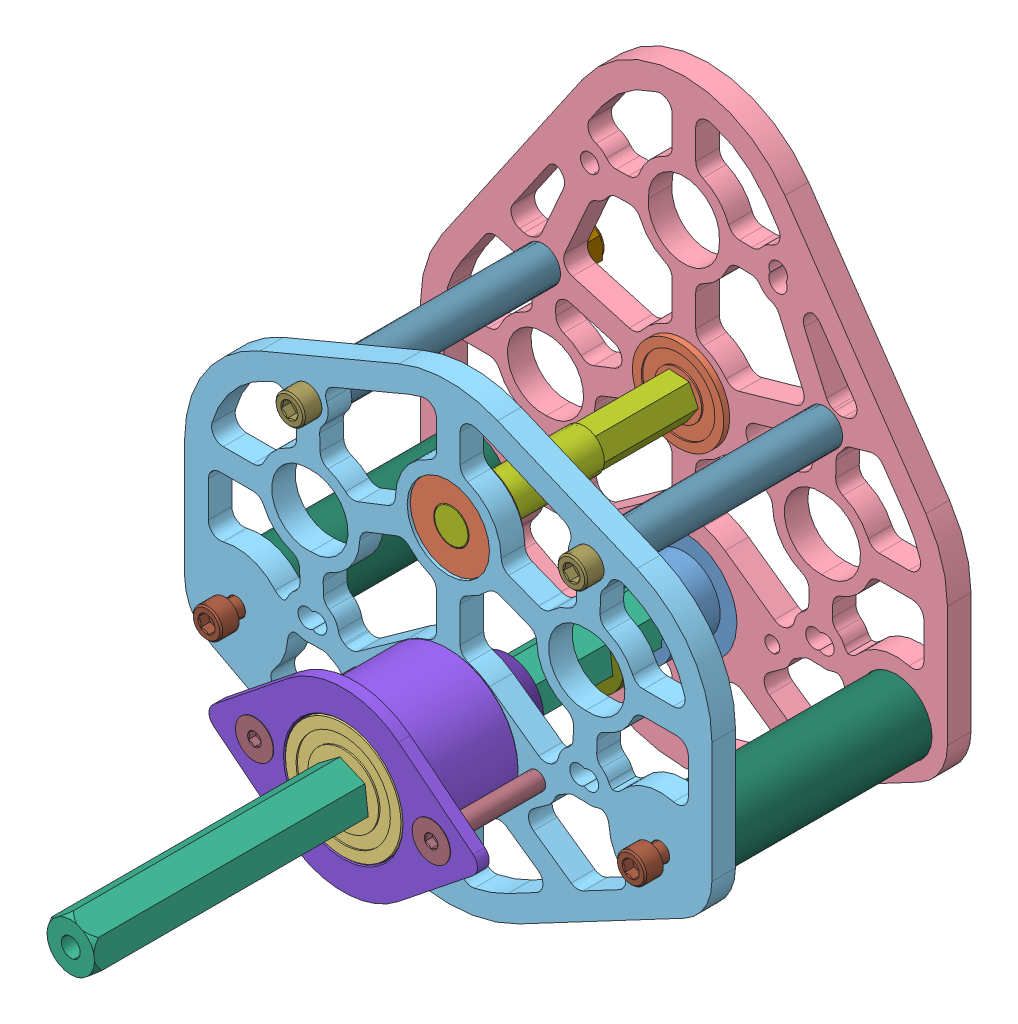
SolidWorks assembly WCP SS Gearbox, configuration Default. Lengths in mm.
Overall size (142.06 161.39 181.1).
30 component instances, 20 part files, 62 mates.
Components (placement in the parent):
- 217-2731-1: 217-2731 [Default] at (0 -47.0408 6.35) x (0.182541 -0.983198 0) z (0.983198 0.182541 0) size (31.12 7.94 31.12)
- 217-2733-1: 217-2733 [Default] at (0 0 7.9375) x (0 0 -1) z (0.981737 -0.190242 0) size (7.11 24.61 24.61)
- 217-2733-2: 217-2733 [Default] at (0 0 61.9125) x (0 0 1) z (-0.773016 -0.634387 0) size (7.11 24.61 24.61)
- 217-2734-1: 217-2734 [Default] at (0 -47.0408 90.2335) x (0.800075 0.5999 0) z (0.5999 -0.800075 0) size (31.12 7.94 31.12)
- 217-3421-001 Rev1-1: 217-3421-001 Rev1 [Default] at origin size (142.02 161.39 6.35)
- 217-3421-002 Rev1-1: 217-3421-002 Rev1 [Default] at (0 0 69.85) x (-1 0 0) z (0 0 -1) size (142.06 121.97 6.35)
- 217-3421-004 Rev1-1: 217-3421-004 Rev1 [Default] at (-0.0106 -47.0363 89.027) x (-0.919566 0.392935 0) z (0 0 1) size (15.59 12.7 175.64)
- 217-3422-001 Rev1-1: 217-3422-001 Rev1 [Default] at (0 0 34.925) x (0.99796 -0.063837 0) z (0 0 1) size (11.11 11.11 68.26)
- 217-3422-004 Rev2-1: 217-3422-004 Rev2 [Default] at (0 -47.0408 96.5835) size (72.39 47.62 34.67)
- 217-3421-010 Rev1-1: 217-3421-010 Rev1 [Default] at (57.15 -47.0408 0) x (0.608161 -0.793814 0) z (0.793814 0.608161 0) size (9.53 6.13 11)
- 217-3421-010 Rev1-2: 217-3421-010 Rev1 [Default] at (-57.15 -47.0408 0) x (0.608161 -0.793814 0) z (0.793814 0.608161 0) size (9.53 6.13 11)
- 217-3421-011 Rev2_97633A200-1: 217-3421-011 Rev2_97633A200 [Default] at (-0.0106 -47.0363 -2.032) x (0 0 -1) z (0.969555 0.244872 0) size (0.89 16.1 14.34)
- 217-3422-005 Rev1-1: 217-3422-005 Rev1 [Default] at (57.15 -47.0408 73.025) x (0 0 -1) z (-0.705988 0.708224 0) size (87.6 7.92 7.92)
- 217-3422-005 Rev1-2: 217-3422-005 Rev1 [Default] at (-57.15 -47.0408 73.025) x (0 0 -1) z (-0.705988 0.708224 0) size (87.6 7.92 7.92)
- 217-3422-006 Rev1-1: 217-3422-006 Rev1 [Default] at (38.0118 10.8086 69.85) x (0 0 -1) z (-0.961271 0.275605 0) size (81.25 7.92 7.92)
- 217-3422-006 Rev1-2: 217-3422-006 Rev1 [Default] at (-38.0118 10.8086 69.85) x (0 0 -1) z (-0.961271 0.275605 0) size (81.25 7.92 7.92)
- 217-3422-007 Rev1-1: 217-3422-007 Rev1 [Default] at (23.8125 -47.0408 95.0723) x (0 0 1) z (-0.888615 -0.458653 0) size (35.11 10.21 10.21)
- 217-3422-007 Rev1-2: 217-3422-007 Rev1 [Default] at (-23.8125 -47.0408 95.0723) x (0 0 1) z (-0.86839 -0.495881 0) size (35.11 10.21 10.21)
- 217-3422-002 Rev1-1: 217-3422-002 Rev1 [Default] at (-38.0118 10.8086 34.925) size (9.53 9.53 57.15)
- 217-3422-002 Rev1-2: 217-3422-002 Rev1 [Default] at (38.0118 10.8086 34.925) size (9.53 9.53 57.15)
- 217-3422-003 Rev1-1: 217-3422-003 Rev1 [Default] at (-57.15 -47.0408 34.925) x (0.999998 0.002183 0) z (0 0 1) size (19.13 19.13 63.5)
- 217-3422-003 Rev1-2: 217-3422-003 Rev1 [Default] at (57.15 -47.0408 34.925) x (0.852021 0.523507 0) z (0 0 1) size (19.13 19.13 63.5)
- 217-3257-001 Rev1-1: 217-3257-001 Rev1 [Default] at (0 -47.0408 31.5785) x (0.800075 0.5999 0) z (0 0 1) size (19.5 19.5 1.59)
- 217-2758-001 Rev1-1: 217-2758-001 Rev1 [Default] at (0 -47.0408 55.3085) x (-0.5999 0.800075 0) z (0 0 1) size (19.05 19.05 3.17)
- 217-3259-001 Rev1-1: 217-3259-001 Rev1 [Default] at (0 -47.0408 60.071) x (-0.919566 0.392935 0) z (0 0 1) size (19.5 19.5 6.35)
- 217-3261-001 Rev1-1: 217-3261-001 Rev1 [Default] at (0 -47.0408 12.7) size (19.5 19.5 12.7)
- 217-3263-001 Rev1-1: 217-3263-001 Rev1 [Default] at (0 -47.0408 77.5335) x (0.919566 -0.392935 0) z (0 0 1) size (19.5 19.5 25.4)
- 217-3257-001 Rev1-2: 217-3257-001 Rev1 [Default] at (0 -47.0408 64.0398) x (0.800075 0.5999 0) z (0 0 1) size (19.5 19.5 1.59)
- 217-3421-010 Rev1-3: 217-3421-010 Rev1 [Default] at (38.0118 10.8086 0) x (0.608161 -0.793814 0) z (0.793814 0.608161 0) size (9.53 6.13 11)
- 217-3421-010 Rev1-4: 217-3421-010 Rev1 [Default] at (-38.0118 10.8086 0) x (0.608161 -0.793814 0) z (0.793814 0.608161 0) size (9.53 6.13 11)
Mates (geometry in assembly coordinates):
- Coincident2: coincident anti-aligned: plane of 217-2734-1 through (-0.8775 -39.7495 90.2335) normal (0.5999 -0.800075 0); plane of 217-3421-004 Rev1-1 through (-0.8868 -39.7564 171.577) normal (-0.5999 0.800075 0)
- Coincident3: coincident anti-aligned: plane of 217-2734-1 through (-6.7532 -44.1551 90.2335) normal (0.992835 0.119491 0); plane of 217-3421-004 Rev1-1 through (-6.7532 -44.1551 171.577) normal (-0.992835 -0.119491 0)
- Concentric1: concentric anti-aligned: cylinder of 217-2734-1 through (0 -47.0408 90.2335) axis (0 0 1) radius 14.2748; cylinder of 217-3422-004 Rev2-1 through (0 -47.0408 98.171) axis (0 0 -1) radius 14.2748
- Coincident4: coincident anti-aligned: plane of 217-2734-1 through (12.4472 -37.7079 96.5835) normal (0 0 -1); plane of 217-3422-004 Rev2-1 through (0 -47.0408 96.5835) normal (0 0 1)
- Concentric2: concentric aligned: cylinder of 217-3422-004 Rev2-1 through (23.8125 -47.0408 98.171) axis (0 0 1) radius 2.5527; cylinder of 217-3422-007 Rev1-1 through (23.8125 -47.0408 63.3731) axis (0 0 1) radius 2.413
- Coincident6: coincident anti-aligned: plane of 217-3422-004 Rev2-1 through (0 -47.0408 98.171) normal (0 0 1); circle of 217-3422-007 Rev1-1
- Concentric5: concentric aligned: cylinder of 217-3422-004 Rev2-1 through (-23.8125 -47.0408 98.171) axis (0 0 1) radius 2.5527; cylinder of 217-3422-007 Rev1-2 through (-23.8125 -47.0408 63.3731) axis (0 0 1) radius 2.413
- Coincident7: coincident anti-aligned: plane of 217-3422-004 Rev2-1 through (0 -47.0408 98.171) normal (0 0 1); circle of 217-3422-007 Rev1-2
- Coincident10: coincident anti-aligned: plane of 217-2734-1 through (11.4209 -38.4773 90.2335) normal (0 0 -1); plane of 217-3263-001 Rev1-1 through (0 -47.0408 90.2335) normal (0 0 1)
- Coincident13: coincident anti-aligned: plane of 217-3263-001 Rev1-1 through (0 -47.0408 64.8335) normal (0 0 -1); plane of 217-3257-001 Rev1-2 through (0 -47.0408 64.8335) normal (0 0 1)
- Parallel1: parallel anti-aligned: plane of 217-3421-004 Rev1-1 through (0.8655 -54.3161 171.577) normal (0.5999 -0.800075 0); plane of 217-3263-001 Rev1-1 through (0.8937 -54.4662 90.2335) normal (-0.5999 0.800075 0)
- Concentric6: concentric anti-aligned: cylinder of 217-2734-1 through (0 -47.0408 90.2335) axis (0 0 1) radius 14.2748; cylinder of 217-3263-001 Rev1-1 through (0 -47.0408 90.2335) axis (0 0 -1) radius 9.75
- Parallel2: parallel anti-aligned: plane of 217-3421-004 Rev1-1 through (-0.8868 -39.7564 171.577) normal (-0.5999 0.800075 0); plane of 217-3257-001 Rev1-2 through (-0.8937 -39.6154 64.8335) normal (0.5999 -0.800075 0)
- Concentric7: concentric aligned: cylinder of 217-3263-001 Rev1-1 through (0 -47.0408 90.2335) axis (0 0 -1) radius 9.75; cylinder of 217-3257-001 Rev1-2 through (0 -47.0408 64.8335) axis (0 0 -1) radius 9.75
- Parallel4: parallel anti-aligned: plane of 217-3421-004 Rev1-1 through (-0.8868 -39.7564 171.577) normal (-0.5999 0.800075 0); plane of 217-3259-001 Rev1-1 through (-0.8937 -39.6154 63.246) normal (0.5999 -0.800075 0)
- Concentric9: concentric aligned: cylinder of 217-3259-001 Rev1-1 through (0 -47.0408 63.246) axis (0 0 -1) radius 9.75; cylinder of 217-3257-001 Rev1-2 through (0 -47.0408 64.8335) axis (0 0 -1) radius 9.75
- Coincident18: coincident anti-aligned: plane of 217-3259-001 Rev1-1 through (0 -47.0408 63.246) normal (0 0 1); plane of 217-3257-001 Rev1-2 through (0 -47.0408 63.246) normal (0 0 -1)
- Concentric10: concentric anti-aligned: cylinder of 217-3421-002 Rev1-1 through (0 -47.0408 63.5) axis (0 0 1) radius 14.2748; cylinder of 217-3422-004 Rev2-1 through (0 -47.0408 123.7315) axis (0 0 -1) radius 14.2621
- Concentric12: concentric anti-aligned: cylinder of 217-3421-002 Rev1-1 through (-23.8125 -47.0408 63.5) axis (0 0 -1) radius 2.0193; cylinder of 217-3422-007 Rev1-2 through (-23.8125 -47.0408 63.3731) axis (0 0 1) radius 2.413
- Coincident19: coincident aligned: plane of 217-3421-002 Rev1-1 through (0 0 69.85) normal (0 0 1); circle of 217-3422-004 Rev2-1
- Concentric13: concentric aligned: cylinder of 217-3421-002 Rev1-1 through (-57.15 -47.0408 66.675) axis (0 0 -1) radius 9.5885; cylinder of 217-3422-003 Rev1-1 through (-57.15 -47.0408 66.675) axis (0 0 -1) radius 9.5631
- Coincident20: coincident anti-aligned: plane of 217-3421-002 Rev1-1 through (-57.15 -47.0408 66.675) normal (0 0 -1); plane of 217-3422-003 Rev1-1 through (-57.15 -47.0408 66.675) normal (0 0 1)
- Concentric14: concentric aligned: cylinder of 217-3421-002 Rev1-1 through (57.15 -47.0408 66.675) axis (0 0 -1) radius 9.5885; cylinder of 217-3422-003 Rev1-2 through (57.15 -47.0408 66.675) axis (0 0 -1) radius 9.5631
- Coincident21: coincident anti-aligned: plane of 217-3421-002 Rev1-1 through (57.15 -47.0408 66.675) normal (0 0 -1); plane of 217-3422-003 Rev1-2 through (57.15 -47.0408 66.675) normal (0 0 1)
- Concentric15: concentric aligned: cylinder of 217-3421-002 Rev1-1 through (57.15 -47.0408 63.5) axis (0 0 1) radius 2.4892; cylinder of 217-3422-005 Rev1-1 through (57.15 -47.0408 -9.525) axis (0 0 1) radius 2.413
- Distance1: distance = 3.175 mm anti-aligned: plane of 217-3421-002 Rev1-1 through (0 0 69.85) normal (0 0 1); plane of 217-3422-005 Rev1-1 through (54.3437 -49.8382 73.025) normal (0 0 -1)
- Concentric16: concentric aligned: cylinder of 217-3421-002 Rev1-1 through (-57.15 -47.0408 63.5) axis (0 0 1) radius 2.4892; cylinder of 217-3422-005 Rev1-2 through (-57.15 -47.0408 -9.525) axis (0 0 1) radius 2.413
- Distance2: distance = 3.175 mm anti-aligned: plane of 217-3421-002 Rev1-1 through (0 0 69.85) normal (0 0 1); plane of 217-3422-005 Rev1-2 through (-59.9563 -49.8382 73.025) normal (0 0 -1)
- Concentric17: concentric aligned: cylinder of 217-3257-001 Rev1-1 through (0 -47.0408 32.3723) axis (0 0 -1) radius 9.75; cylinder of 217-3259-001 Rev1-1 through (0 -47.0408 63.246) axis (0 0 -1) radius 9.75
- Parallel5: parallel anti-aligned: plane of 217-3421-004 Rev1-1 through (5.8558 -42.6376 171.577) normal (0.392935 0.919566 0); plane of 217-3257-001 Rev1-1 through (5.9838 -42.5541 32.3723) normal (-0.392935 -0.919566 0)
- Concentric18: concentric aligned: cylinder of 217-2758-001 Rev1-1 through (0 -47.0408 56.896) axis (0 0 -1) radius 9.525; cylinder of 217-3259-001 Rev1-1 through (0 -47.0408 63.246) axis (0 0 -1) radius 9.75
- Parallel6: parallel anti-aligned: plane of 217-3421-004 Rev1-1 through (-0.8868 -39.7564 171.577) normal (-0.5999 0.800075 0); plane of 217-2758-001 Rev1-1 through (-0.8937 -39.6154 56.896) normal (0.5999 -0.800075 0)
- Coincident28: coincident anti-aligned: plane of 217-2758-001 Rev1-1 through (0 -47.0408 56.896) normal (0 0 1); plane of 217-3259-001 Rev1-1 through (0 -47.0408 56.896) normal (0 0 -1)
- Distance3: distance = 21.3487 mm anti-aligned: plane of 217-2758-001 Rev1-1 through (0 -47.0408 53.721) normal (0 0 -1); plane of 217-3257-001 Rev1-1 through (0 -47.0408 32.3723) normal (0 0 1)
- Concentric19: concentric anti-aligned: cylinder of 217-2733-2 through (0 0 61.9125) axis (0 0 -1) radius 11.1125; cylinder of 217-3421-002 Rev1-1 through (0 0 63.5) axis (0 0 1) radius 11.0998
- Coincident31: coincident anti-aligned: plane of 217-2733-2 through (-7.0496 8.5901 63.5) normal (0 0 1); plane of 217-3421-002 Rev1-1 through (0 0 63.5) normal (0 0 -1)
- Concentric20: concentric aligned: cylinder of 217-2733-2 through (0 0 61.9125) axis (0 0 -1) radius 4.7625; cylinder of 217-3422-001 Rev1-1 through (0 0 69.0563) axis (0 0 -1) radius 4.7498
- Coincident32: coincident anti-aligned: plane of 217-2733-2 through (-4.0284 4.9086 61.9125) normal (0 0 -1); plane of 217-3422-001 Rev1-1 through (0 0 61.9125) normal (0 0 1)
- Concentric24: concentric aligned: cylinder of 217-2731-1 through (0 -47.0408 6.35) axis (0 0 -1) radius 14.2875; cylinder of 217-3421-001 Rev1-1 through (0 -47.0408 6.35) axis (0 0 -1) radius 14.2748
- Coincident38: coincident anti-aligned: plane of 217-2731-1 through (2.8399 -62.3369 0) normal (0 0 1); plane of 217-3421-001 Rev1-1 through (0 0 0) normal (0 0 -1)
- Concentric25: concentric aligned: cylinder of 217-2731-1 through (0 -47.0408 6.35) axis (0 0 -1) radius 6.35; cylinder of 217-3261-001 Rev1-1 through (0 -47.0408 19.05) axis (0 0 -1) radius 9.75
- Coincident39: coincident anti-aligned: plane of 217-2731-1 through (2.6081 -61.0882 6.35) normal (0 0 1); plane of 217-3261-001 Rev1-1 through (0 -47.0408 6.35) normal (0 0 -1)
- Concentric27: concentric aligned: cylinder of 217-3421-004 Rev1-1 through (-0.0106 -47.0363 -2.4765) axis (0 0 1) radius 5.9436; cylinder of 217-3421-011 Rev2_97633A200-1 through (-0.0106 -47.0363 -2.4765) axis (0 0 1) radius 5.8547
- Coincident42: coincident anti-aligned: plane of 217-3421-011 Rev2_97633A200-1 through (-0.0106 -47.0363 -2.4765) normal (0 0 -1); plane of 217-3421-004 Rev1-1 through (-0.0106 -47.0363 -2.4765) normal (0 0 1)
- Concentric34: concentric: cylinder of 217-3421-002 Rev1-1 through (38.0118 10.8086 63.5) axis (0 0 1) radius 2.4892; cylinder of 217-3422-006 Rev1-1 through (38.0118 10.8086 -6.35) axis (0 0 1) radius 2.413
- Coincident50: coincident: plane of 217-3421-002 Rev1-1 through (0 0 69.85) normal (0 0 1); plane of 217-3422-006 Rev1-1 through (36.9198 6.9997 69.85) normal (0 0 -1)
- Concentric35: concentric: cylinder of 217-3421-002 Rev1-1 through (-38.0118 10.8086 63.5) axis (0 0 1) radius 2.4892; cylinder of 217-3422-006 Rev1-2 through (-38.0118 10.8086 -6.35) axis (0 0 1) radius 2.413
- Coincident51: coincident: plane of 217-3421-002 Rev1-1 through (0 0 69.85) normal (0 0 1); plane of 217-3422-006 Rev1-2 through (-39.1039 6.9997 69.85) normal (0 0 -1)
- Concentric36: concentric: cylinder of 217-3422-006 Rev1-2 through (-38.0118 10.8086 -6.35) axis (0 0 1) radius 2.413; cylinder of 217-3422-002 Rev1-1 through (-38.0118 10.8086 63.5) axis (0 0 -1) radius 2.5527
- Coincident52: coincident anti-aligned: plane of 217-3421-002 Rev1-1 through (0 0 63.5) normal (0 0 -1); plane of 217-3422-002 Rev1-1 through (-38.0118 10.8086 63.5) normal (0 0 1)
- Concentric37: concentric: cylinder of 217-3422-006 Rev1-1 through (38.0118 10.8086 -6.35) axis (0 0 1) radius 2.413; cylinder of 217-3422-002 Rev1-2 through (38.0118 10.8086 63.5) axis (0 0 -1) radius 2.5527
- Coincident53: coincident anti-aligned: plane of 217-3421-002 Rev1-1 through (0 0 63.5) normal (0 0 -1); plane of 217-3422-002 Rev1-2 through (38.0118 10.8086 63.5) normal (0 0 1)
- Concentric41: concentric aligned: cylinder of 217-2733-1 through (0 0 7.9375) axis (0 0 1) radius 4.7625; cylinder of 217-3422-001 Rev1-1 through (0 0 0.7937) axis (0 0 1) radius 4.7498
- Concentric42: concentric anti-aligned: cylinder of 217-2733-1 through (0 0 7.9375) axis (0 0 1) radius 11.1125; cylinder of 217-3421-001 Rev1-1 through (0 0 6.35) axis (0 0 -1) radius 11.0998
- Coincident54: coincident anti-aligned: plane of 217-2733-1 through (2.1141 10.9096 6.35) normal (0 0 -1); plane of 217-3421-001 Rev1-1 through (0 0 6.35) normal (0 0 1)
- Concentric48: concentric anti-aligned: cylinder of 217-3421-001 Rev1-1 through (57.15 -47.0408 3.175) axis (0 0 1) radius 9.7155; cylinder of 217-3422-003 Rev1-2 through (57.15 -47.0408 66.675) axis (0 0 -1) radius 9.5631
- Coincident61: coincident anti-aligned: plane of 217-3421-001 Rev1-1 through (57.15 -47.0408 3.175) normal (0 0 1); plane of 217-3422-003 Rev1-2 through (57.15 -47.0408 3.175) normal (0 0 -1)
- Coincident63: coincident anti-aligned: plane of 217-2731-1 through (1.1591 -53.2841 -1.5875) normal (0 0 -1); plane of 217-3421-011 Rev2_97633A200-1 through (-0.0106 -47.0363 -1.5875) normal (0 0 1)
- Concentric49: concentric: cylinder of 217-3422-006 Rev1-1 through (38.0118 10.8086 -6.35) axis (0 0 1) radius 2.413; cylinder of 217-3421-010 Rev1-3 through (38.0118 10.8086 -5.0371) axis (0 0 1) radius 2.0454
- Coincident64: coincident anti-aligned: plane of 217-3421-001 Rev1-1 through (0 0 0) normal (0 0 -1); plane of 217-3421-010 Rev1-3 through (33.6465 7.4642 0) normal (0 0 1)
- Concentric50: concentric: cylinder of 217-3422-006 Rev1-2 through (-38.0118 10.8086 -6.35) axis (0 0 1) radius 2.413; cylinder of 217-3421-010 Rev1-4 through (-38.0118 10.8086 -5.0371) axis (0 0 1) radius 2.0454
- Coincident65: coincident anti-aligned: plane of 217-3421-001 Rev1-1 through (0 0 0) normal (0 0 -1); plane of 217-3421-010 Rev1-4 through (-42.3772 7.4642 0) normal (0 0 1)
